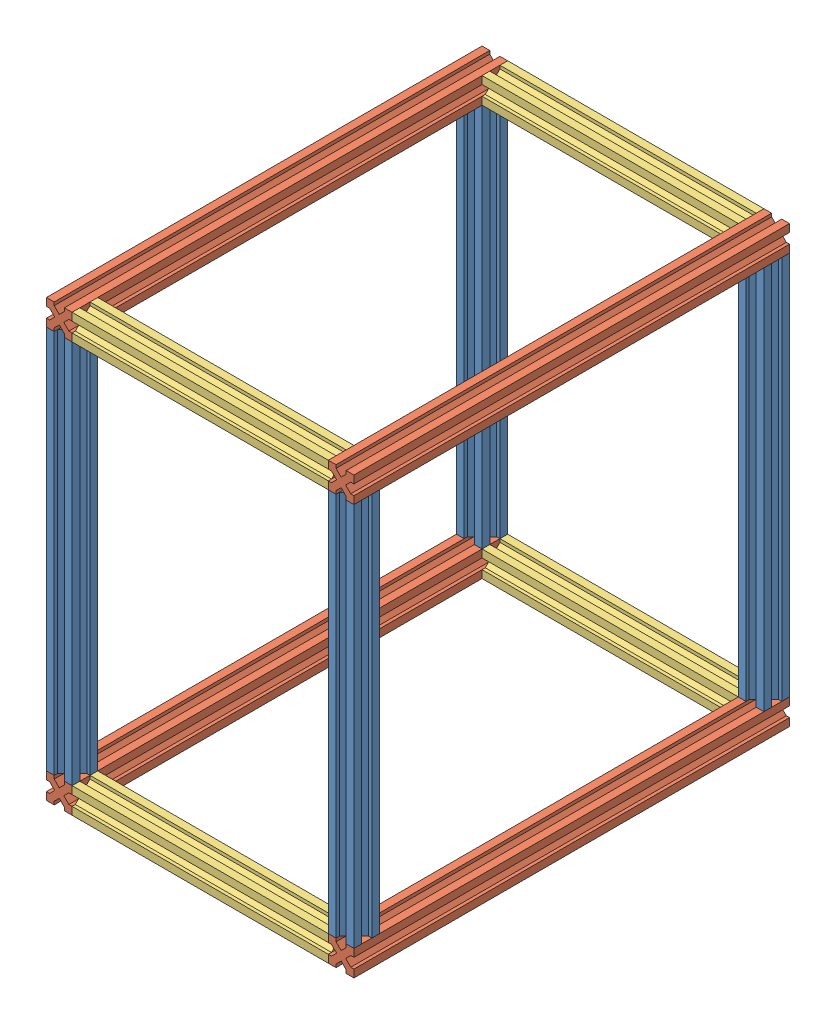
SolidWorks assembly module interne 1.0, configuration Défaut. Lengths in mm.
Overall size (240 340 340).
12 component instances, 3 part files, 33 mates.
Components (placement in the parent):
- profilé 300-1: profilé 300 [Défaut] at (-15.1124 -153.9745 312.5) size (20 300 20)
- profilé 340-1: profilé 340 [Défaut] at (-35.1124 146.0255 312.5) x (-1 0 0) z (0 -1 0) size (20 340 20)
- profilé 340-2: profilé 340 [Défaut] at (-15.1124 -173.9745 -27.5) x (1 0 0) z (0 -1 0) size (20 340 20)
- profilé 300-2: profilé 300 [Défaut] at (-35.1124 -153.9745 -27.5) x (-1 0 0) z (0 0 -1) size (20 300 20)
- profilé 200-1: profilé 200 [Défaut] at (184.8876 146.0255 292.5) x (0 -1 0) z (0 0 -1) size (20 200 20)
- profilé 200-2: profilé 200 [Défaut] at (-15.1124 -173.9745 292.5) x (0 0 -1) z (0 -1 0) size (20 200 20)
- profilé 200-3: profilé 200 [Défaut] at (-15.1124 -153.9745 -7.5) x (0 0 1) z (0 1 0) size (20 200 20)
- profilé 200-4: profilé 200 [Défaut] at (184.8876 146.0255 -7.5) x (0 0 1) z (0 -1 0) size (20 200 20)
- profilé 340-3: profilé 340 [Défaut] at (184.8876 146.0255 -27.5) x (0 -1 0) z (-1 0 0) size (20 340 20)
- profilé 340-4: profilé 340 [Défaut] at (184.8876 -173.9745 -27.5) x (0 -1 0) z (-1 0 0) size (20 340 20)
- profilé 300-3: profilé 300 [Défaut] at (184.8876 -153.9745 -27.5) x (-1 0 0) z (0 0 -1) size (20 300 20)
- profilé 300-4: profilé 300 [Défaut] at (204.8876 -153.9745 312.5) size (20 300 20)
Mates (geometry in assembly coordinates):
- Coïncidente9: coincident: point of profilé 300-1; point of profilé 340-1
- Coïncidente11: coincident: point of profilé 300-1; point of profilé 340-1
- Coïncidente12: coincident: point of profilé 300-1; line of profilé 340-1 through (-15.1124 146.0255 -27.5) axis (0 0 1)
- Coïncidente13: coincident: point of profilé 300-1; point of profilé 340-2
- Coïncidente14: coincident: point of profilé 300-1; point of profilé 340-2
- Coïncidente15: coincident: point of profilé 300-1; line of profilé 340-2 through (-35.1124 -153.9745 312.5) axis (0 0 -1)
- Coïncidente16: coincident: point of profilé 340-1; point of profilé 300-2
- Coïncidente21: coincident: point of profilé 340-1; point of profilé 300-2
- Coïncidente22: coincident: line of profilé 340-1 through (-15.1124 146.0255 -27.5) axis (0 0 1); point of profilé 300-2
- Coïncidente23: coincident: point of profilé 340-1; point of profilé 200-1
- Coïncidente24: coincident: point of profilé 300-1; point of profilé 200-1
- Coïncidente28: coincident: point of profilé 300-1; point of profilé 200-1
- Coïncidente29: coincident: point of profilé 300-1; point of profilé 200-2
- Coïncidente30: coincident: point of profilé 300-1; point of profilé 200-2
- Coïncidente31: coincident: point of profilé 340-2; point of profilé 200-2
- Coïncidente32: coincident: point of profilé 340-2; point of profilé 200-3
- Coïncidente33: coincident: point of profilé 300-2; point of profilé 200-3
- Coïncidente34: coincident: point of profilé 340-2; point of profilé 200-3
- Coïncidente35: coincident: point of profilé 340-1; point of profilé 200-4
- Coïncidente36: coincident: point of profilé 300-2; point of profilé 200-4
- Coïncidente37: coincident: point of profilé 340-1; point of profilé 200-4
- Coïncidente38: coincident: point of profilé 200-4; point of profilé 340-3
- Coïncidente39: coincident: point of profilé 200-4; point of profilé 340-3
- Coïncidente40: coincident: point of profilé 200-4; line of profilé 340-3 through (184.8876 146.0255 312.5) axis (0 0 -1)
- Coïncidente41: coincident: point of profilé 200-2; point of profilé 340-4
- Coïncidente42: coincident: point of profilé 200-2; point of profilé 340-4
- Coïncidente43: coincident: point of profilé 200-2; line of profilé 340-4 through (184.8876 -173.9745 312.5) axis (0 0 -1)
- Coïncidente44: coincident: point of profilé 340-3; point of profilé 300-3
- Coïncidente50: coincident: point of profilé 340-3; point of profilé 300-3
- Coïncidente51: coincident: line of profilé 340-3 through (204.8876 146.0255 312.5) axis (0 0 -1); point of profilé 300-3
- Coïncidente52: coincident: point of profilé 340-3; point of profilé 300-4
- Coïncidente53: coincident: line of profilé 340-3 through (204.8876 146.0255 312.5) axis (0 0 -1); point of profilé 300-4
- Coïncidente54: coincident: point of profilé 200-1; point of profilé 300-4
